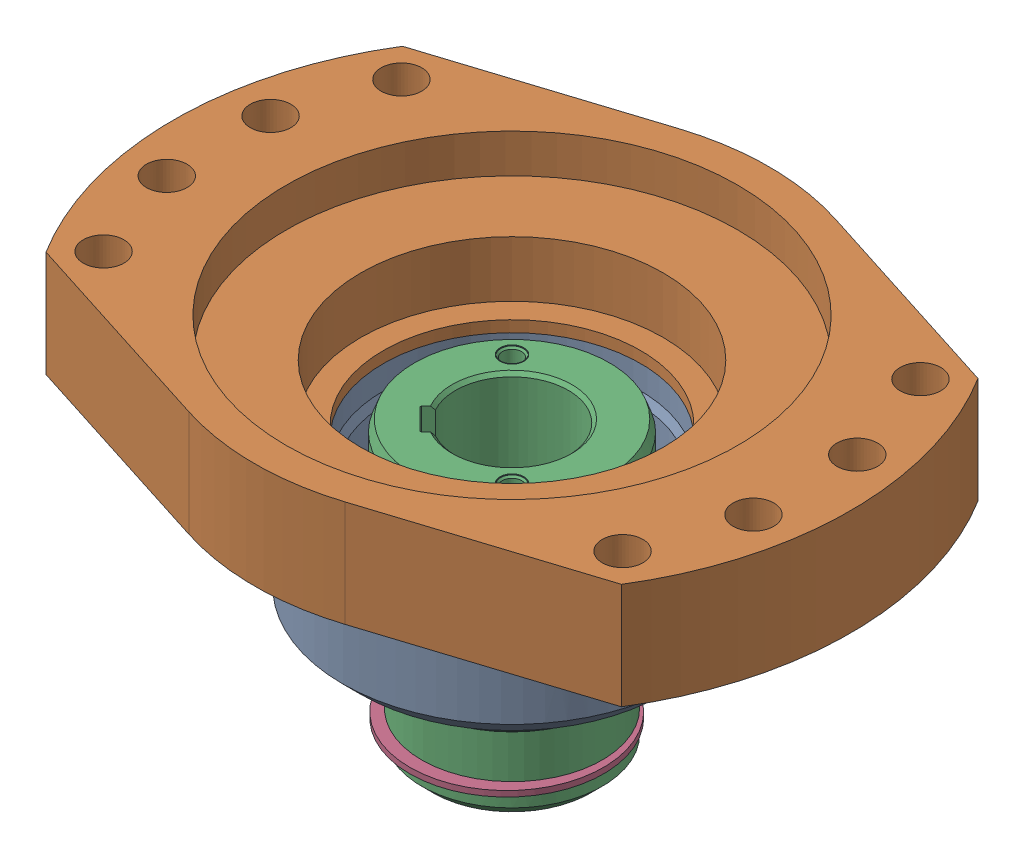
SolidWorks assembly g1_3_1_1_1_2, configuration 默认. Lengths in mm.
Overall size (300 165.8 228).
5 component instances, 4 part files, 0 mates.
Components (placement in the parent):
- g1_3_1_1_1_1_1-1: g1_3_1_1_1_1_1 [默认] at origin size (300 112 228)
  - g1_3_1_1_1_1-2_af0_1-1: g1_3_1_1_1_1-2_af0_1 [默认] at (0 50 0) size (150 65 150)
  - g1_3_1_1_1_1-3_af0_1-1: g1_3_1_1_1_1-3_af0_1 [默认] at (0 140 0) size (300 47 228)
- g1_3_1_1_1-2_1-1: g1_3_1_1_1-2_1 [默认] at (0 122.2 0) x (0.707107 0 0.707107) z (0.707107 0 -0.707107) size (90 126 90)
- 80_gb894_1_1-1: 80_gb894_1_1 [默认] at (-2.4 11.1 -38.1746) x (1 0 0) z (0 -1 0) size (85.83 90.87 2.5)
